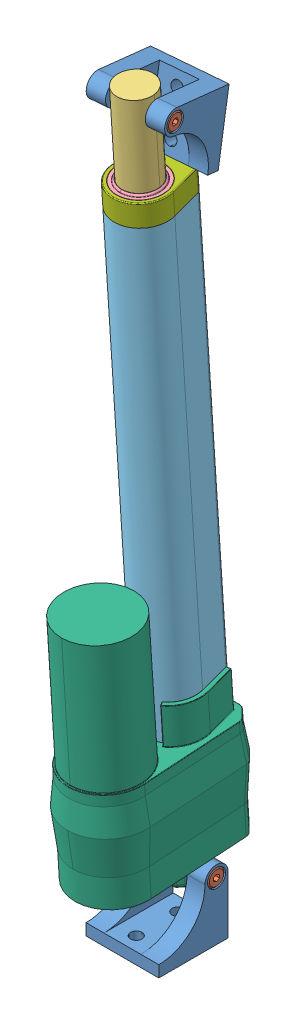
SolidWorks assembly _test - w-celvis.STEP, configuration Default. Lengths in mm.
Overall size (45.52 413.33 110.1).
12 component instances, 7 part files, 0 mates.
Components (placement in the parent):
- Celvis w-bolt.STEP-1: Celvis w-bolt.STEP [Default] at (-1.8316 365.9876 -31.3367) x (0.996622 0.005361 -0.081949) z (0.019869 -0.983961 0.177274) size (40.02 38.14 38.14)
  - HDA Clevis Mount.STEP-1: HDA Clevis Mount.STEP [Default] at origin size (40 38.1 38.1)
  - Shoulder Bolt .25 x  1 - 10-24_SHSSCREW 0.25x1-N.STEP-1: Shoulder Bolt .25 x  1 - 10-24_SHSSCREW 0.25x1-N.STEP [Default] at (40.0177 31.75 -31.75) x (-1 0 0) z (0 0.894783 -0.446501) size (39.7 9.53 9.53)
- Celvis w-bolt.STEP-2: Celvis w-bolt.STEP [Default] at origin size (40.02 38.14 38.14)
  - HDA Clevis Mount.STEP-1: HDA Clevis Mount.STEP [Default] at origin size (40 38.1 38.1)
  - Shoulder Bolt .25 x  1 - 10-24_SHSSCREW 0.25x1-N.STEP-1: Shoulder Bolt .25 x  1 - 10-24_SHSSCREW 0.25x1-N.STEP [Default] at (40.0177 31.75 -31.75) x (-1 0 0) z (0 0.894783 -0.446501) size (39.7 9.53 9.53)
- HDA-8-2.STEP-1: HDA-8-2.STEP [Default] at (20.0025 43.1556 -31.0039) x (1 0 0) z (0 -0.065273 0.997867) size (45.52 389.44 84.86)
  - HDA-STROKE_8IN.STEP-1: HDA-STROKE_8IN.STEP [Default] at (0 369.5002 0) x (0.082124 0 0.996622) z (0.996622 0 -0.082124) size (19.94 220.98 20.03)
  - HDA-CAP-SEAL.STEP-1: HDA-CAP-SEAL.STEP [Default] at (0 320.294 0) size (26.42 3.52 26.42)
  - HDA-SHROUD_8IN.STEP-1: HDA-SHROUD_8IN.STEP [Default] at (0 56.642 0) size (30.48 254 36.83)
  - HDA-BASE.STEP-1: HDA-BASE.STEP [Default] at origin size (45.52 149.35 84.86)
  - HDA-SHROUD-CAP.STEP-1: HDA-SHROUD-CAP.STEP [Default] at (0 310.642 0) size (30.48 12.19 36.83)
